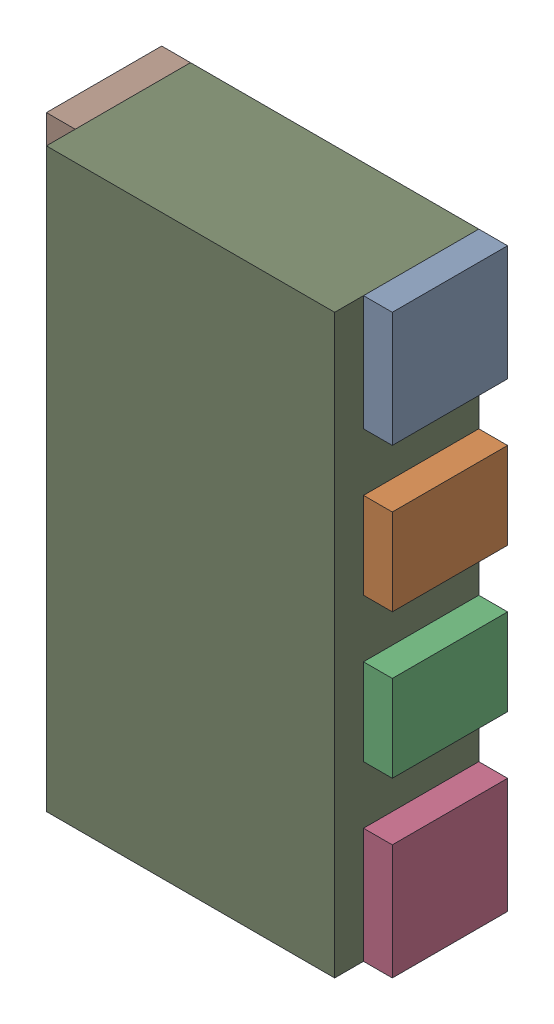
SolidWorks assembly RN3, configuration Default. Lengths in mm.
Overall size (1.2 2 0.5).
18 component instances, 3 part files, 0 mates.
Components (placement in the parent):
- 791587232-1: 791587232 [Default] at (108.6 19.45 0) size (0.1 0.4 0.4)
  - Extruded_10-1: Extruded_10 [Default] at origin size (0.1 0.4 0.4)
- 836750576-1: 836750576 [Default] at (108.6 18.9 0) size (0.1 0.3 0.4)
  - Extruded_14-1: Extruded_14 [Default] at origin size (0.1 0.3 0.4)
- 836750576-2: 836750576 [Default] at (108.6 18.4 0) size (0.1 0.3 0.4)
  - Extruded_14-1: Extruded_14 [Default] at origin size (0.1 0.3 0.4)
- 791587232-2: 791587232 [Default] at (108.6 17.85 0) size (0.1 0.4 0.4)
  - Extruded_10-1: Extruded_10 [Default] at origin size (0.1 0.4 0.4)
- 791587232-3: 791587232 [Default] at (107.5 17.85 0) size (0.1 0.4 0.4)
  - Extruded_10-1: Extruded_10 [Default] at origin size (0.1 0.4 0.4)
- 836750576-3: 836750576 [Default] at (107.5 18.4 0) size (0.1 0.3 0.4)
  - Extruded_14-1: Extruded_14 [Default] at origin size (0.1 0.3 0.4)
- 836750576-4: 836750576 [Default] at (107.5 18.9 0) size (0.1 0.3 0.4)
  - Extruded_14-1: Extruded_14 [Default] at origin size (0.1 0.3 0.4)
- 791587232-4: 791587232 [Default] at (107.5 19.45 0) size (0.1 0.4 0.4)
  - Extruded_10-1: Extruded_10 [Default] at origin size (0.1 0.4 0.4)
- 836750320-1: 836750320 [Default] at (108.05 18.65 0) size (1 2 0.5)
  - Extruded_15-1: Extruded_15 [Default] at origin size (1 2 0.5)
